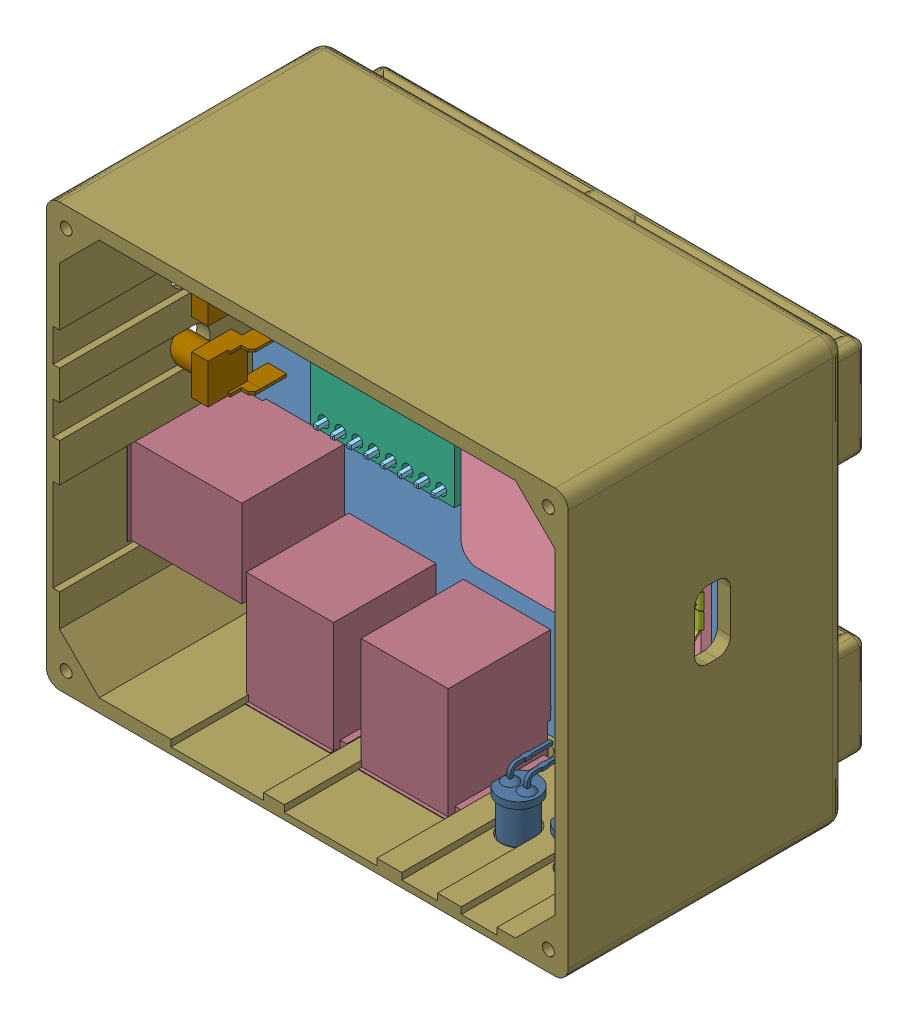
SolidWorks assembly MainDevice, configuration Default. Lengths in mm.
Overall size (81.7 66.7 48).
21 component instances, 16 part files, 51 mates.
Components (placement in the parent):
- main-pcb-1: main-pcb [Default] at (15.5419 -12.6286 71.3403) size (72 56 1.6)
- Pin Header40-1: Pin Header40 [Default] at (39.7853 10.197 72.9403) x (-1 0 0) z (0 0 1) size (51.3 5.33 17.39)
- pinStrip40-1: pinStrip40 [Default] at (-8.2247 9.871 86.5203) x (1 0 0) z (0 0 -1) size (50.8 5.08 11.94)
- Raspberry Pi Zero 2 W-1: Raspberry Pi Zero 2 W [Default] at (15.8053 -2.859 87.0663) x (1 0 0) z (0 -1 0) size (65.8 5.05 30.58) (hidden)
- baterryChargerPCB-1: baterryChargerPCB [Default] at (33.3919 -8.6084 75.4803) x (-1 0 0) z (0 0 1) size (36.3 22.9 1.6)
- 8pins-1: 8pins [Default] at (20.9419 1.6016 78.4803) x (1 0 0) z (0 0 -1) size (20.28 2.5 11.54)
- IMU-PCB-1: IMU-PCB [Default] at (3.3577 -5.3013 75.4803) size (21.8 17.2 1.6)
- 8pins-2: 8pins [Default] at (12.2777 -12.5813 78.4803) x (-1 0 0) z (0 0 -1) size (20.28 2.5 11.54)
- MicroUSB Port, Raspberry Pi Zero 2 W-1: MicroUSB Port, Raspberry Pi Zero 2 W [Default] at (49.3967 -8.6084 77.0803) x (0 1 0) z (1 0 0) size (7.97 2.92 5.43)
- baterryConector-1: baterryConector [Default] at (40.7919 -16.4084 78.6803) x (1 0 0) z (0 -1 0) size (6 7.7 7.3)
- button-1: button [Default] at (-17.2581 3.0321 76.8522) x (0 -1 0) z (-1 0 0) size (6 11.91 9.99)
- button-2: button [Default] at (-17.2581 -7.5747 76.8522) x (0 -1 0) z (-1 0 0) size (6 11.91 9.99)
- led-1: led [Default] at (41.0782 -35.6926 82.166) size (5.41 10.96 9.16)
- led-2: led [Default] at (32.0651 -35.4033 82.177) size (5.41 10.96 9.16)
- battery-1: battery [Default] at (13.9578 -6.0356 69.8403) x (-1 0 0) z (0 0 -1) size (59.2 29.3 9.7)
- encapsuladoMain-1: encapsuladoMain [Default] at (15.0419 -12.6286 58.1403) x (1 0 0) z (0 -1 0) size (79 48 64)
- otg-1: otg [Default] at (-10.4122 -26.7049 90.9313) x (-1 0 0) z (0 0 1) size (36.6 18.2 12.4) (hidden)
- tapa-main-1: tapa-main [Default] at (15.0419 -12.6286 156.1403) x (0 -1 0) z (0 0 -1) size (64 79 6) (hidden)
- rj11jack-1: rj11jack [Default] at (0.7219 -37.0286 72.9403) size (15.2 20.6 20)
- rj11jack-2: rj11jack [Default] at (-16.8581 -24.6336 72.9403) x (0 -1 0) z (0 0 1) size (15.2 20.6 20)
- rj11jack-3: rj11jack [Default] at (18.0719 -37.0286 72.9403) size (15.2 20.6 20)
Mates (geometry in assembly coordinates):
- Coincident5: coincident anti-aligned: plane of main-pcb-1 through (15.5419 -12.6286 72.9403) normal (0 0 1); plane of Pin Header40-1 through (-8.4747 8.927 72.9403) normal (0 0 -1)
- Parallel1: parallel anti-aligned: plane of main-pcb-1 through (47.5419 15.3714 72.9403) normal (0 1 0); plane of Pin Header40-1 through (15.9053 6.141 75.4803) normal (0 -1 0)
- Coincident8: coincident anti-aligned: plane of pinStrip40-1 through (41.0513 11.141 86.2663) normal (0 0 1); plane of Raspberry Pi Zero 2 W-1 through (15.8053 -2.859 86.2663) normal (0 0 -1)
- Parallel2: parallel aligned: plane of pinStrip40-1 through (39.0193 11.141 86.5203) normal (0 1 0); plane of Raspberry Pi Zero 2 W-1 through (-16.6947 12.141 87.8663) normal (0 1 0)
- Distance2: distance = 1 mm aligned: plane of pinStrip40-1 through (39.0193 11.141 86.5203) normal (0 1 0); plane of Raspberry Pi Zero 2 W-1 through (-16.6947 12.141 87.8663) normal (0 1 0)
- Distance3: distance = 7 mm aligned: plane of pinStrip40-1 through (41.3053 8.601 83.9803) normal (1 0 0); plane of Raspberry Pi Zero 2 W-1 through (48.3053 12.141 87.8663) normal (1 0 0)
- Coincident13: coincident anti-aligned: plane of Pin Header40-1 through (15.9053 6.141 83.9803) normal (0 0 1); plane of pinStrip40-1 through (-8.2247 8.601 83.9803) normal (0 0 -1)
- Coincident14: coincident aligned: plane of Pin Header40-1 through (15.9053 11.141 83.9803) normal (0 1 0); plane of pinStrip40-1 through (36.4793 11.141 86.5203) normal (0 1 0)
- Coincident15: coincident aligned: plane of Pin Header40-1 through (41.3053 8.641 75.4803) normal (1 0 0); plane of pinStrip40-1 through (41.3053 8.601 83.9803) normal (1 0 0)
- Coincident16: coincident anti-aligned: plane of baterryChargerPCB-1 through (17.7819 0.3016 75.4803) normal (0 0 -1); plane of 8pins-1 through (20.9419 1.6016 75.4803) normal (0 0 1)
- Parallel4: parallel aligned: plane of baterryChargerPCB-1 through (17.7819 2.8416 77.0803) normal (0 1 0); plane of 8pins-1 through (29.8119 2.8516 75.4803) normal (0 1 0)
- Distance5: distance = 0.01 mm aligned: plane of baterryChargerPCB-1 through (17.7819 2.8416 77.0803) normal (0 1 0); plane of 8pins-1 through (39.9719 2.8516 75.4803) normal (0 1 0)
- Distance6: distance = 11.57 mm aligned: plane of baterryChargerPCB-1 through (51.5419 0.3016 77.0803) normal (1 0 0); plane of 8pins-1 through (39.9719 0.3516 75.4803) normal (1 0 0)
- Coincident21: coincident anti-aligned: plane of main-pcb-1 through (15.5419 -12.6286 72.9403) normal (0 0 1); plane of 8pins-1 through (38.7219 1.6016 72.9403) normal (0 0 -1)
- Coincident22: coincident anti-aligned: plane of IMU-PCB-1 through (3.3577 -5.3013 75.4803) normal (0 0 -1); plane of 8pins-2 through (12.2777 -12.5813 75.4803) normal (0 0 1)
- Parallel5: parallel aligned: plane of IMU-PCB-1 through (14.2577 -13.9013 77.0803) normal (1 0 0); plane of 8pins-2 through (13.5277 -13.8313 75.4803) normal (1 0 0)
- Distance7: distance = 0.07 mm aligned: plane of 8pins-2 through (11.0277 -13.8313 75.4803) normal (0 -1 0); plane of IMU-PCB-1 through (14.2577 -13.9013 77.0803) normal (0 -1 0)
- Distance8: distance = 0.73 mm aligned: plane of 8pins-2 through (13.5277 -13.8313 75.4803) normal (1 0 0); plane of IMU-PCB-1 through (14.2577 -13.9013 77.0803) normal (1 0 0)
- Coincident26: coincident anti-aligned: plane of main-pcb-1 through (15.5419 -12.6286 72.9403) normal (0 0 1); plane of 8pins-2 through (12.2777 -12.5813 72.9403) normal (0 0 -1)
- Coincident27: coincident aligned: plane of main-pcb-1 through (51.5419 -36.6286 72.9403) normal (1 0 0); plane of baterryChargerPCB-1 through (51.5419 0.3016 77.0803) normal (1 0 0)
- Coincident28: coincident anti-aligned: plane of baterryChargerPCB-1 through (17.7819 0.3016 77.0803) normal (0 0 1); plane of MicroUSB Port, Raspberry Pi Zero 2 W-1 through (46.8467 -6.012 77.0803) normal (0 0 -1)
- Parallel6: parallel aligned: plane of baterryChargerPCB-1 through (17.7819 2.8416 77.0803) normal (0 1 0); plane of MicroUSB Port, Raspberry Pi Zero 2 W-1 through (46.8467 -4.8584 78.9803) normal (0 1 0)
- Coincident30: coincident anti-aligned: line of baterryChargerPCB-1 through (51.5419 -17.5184 77.0803) axis (0 1 0); line of MicroUSB Port, Raspberry Pi Zero 2 W-1 through (51.5419 -8.6584 77.0803) axis (0 -1 0)
- Distance9: distance = 7.7 mm aligned: plane of MicroUSB Port, Raspberry Pi Zero 2 W-1 through (46.8467 -4.8584 78.9803) normal (0 1 0); plane of baterryChargerPCB-1 through (17.7819 2.8416 77.0803) normal (0 1 0)
- Coincident34: coincident anti-aligned: plane of baterryChargerPCB-1 through (17.7819 0.3016 77.0803) normal (0 0 1); plane of baterryConector-1 through (42.4169 -20.0584 77.0803) normal (0 0 -1)
- Coincident35: coincident aligned: plane of baterryChargerPCB-1 through (17.7819 -20.0584 77.0803) normal (0 -1 0); plane of baterryConector-1 through (40.7919 -20.0584 78.6803) normal (0 -1 0)
- Distance10: distance = 9.5 mm aligned: plane of baterryConector-1 through (42.0419 -16.4084 78.6803) normal (1 0 0); plane of baterryChargerPCB-1 through (51.5419 0.3016 77.0803) normal (1 0 0)
- Coincident37: coincident anti-aligned: plane of main-pcb-1 through (15.5419 -12.6286 72.9403) normal (0 0 1); plane of button-1 through (-16.3699 3.0321 72.9403) normal (0 0 -1)
- Coincident38: coincident anti-aligned: plane of main-pcb-1 through (15.5419 -12.6286 72.9403) normal (0 0 1); plane of button-2 through (-16.3699 -7.5747 72.9403) normal (0 0 -1)
- Parallel7: parallel aligned: plane of main-pcb-1 through (-20.4581 -36.6286 72.9403) normal (-1 0 0); plane of button-2 through (-19.7581 -7.5747 76.8522) normal (-1 0 0)
- Parallel8: parallel aligned: plane of main-pcb-1 through (-20.4581 -36.6286 72.9403) normal (-1 0 0); plane of button-1 through (-19.7581 3.0321 76.8522) normal (-1 0 0)
- Distance14: distance = 1.5 mm anti-aligned: plane of battery-1 through (13.9578 -6.0356 69.8403) normal (0 0 1); plane of main-pcb-1 through (15.5419 -12.6286 71.3403) normal (0 0 -1)
- Parallel9: parallel aligned: plane of main-pcb-1 through (-20.4581 -36.6286 72.9403) normal (-1 0 0); plane of battery-1 through (-12.1422 -20.6856 60.1403) normal (-1 0 0)
- Coincident41: coincident anti-aligned: plane of battery-1 through (13.9578 -6.0356 60.1403) normal (0 0 -1); plane of encapsuladoMain-1 through (15.0419 -12.6286 60.1403) normal (0 0 1)
- Distance17: distance = 2 mm anti-aligned: plane of encapsuladoMain-1 through (52.5419 -42.6286 100.1403) normal (0 1 0); plane of main-pcb-1 through (47.5419 -40.6286 72.9403) normal (0 -1 0)
- Distance18: distance = 2 mm: plane of encapsuladoMain-1 through (-22.4581 -42.6286 100.1403) normal (1 0 0); line of main-pcb-1 through (-20.4581 11.3714 72.9403) axis (0 -1 0)
- Distance22: distance = 0.8 mm aligned: plane of button-1 through (-25.2581 0.0321 79.8522) normal (-1 0 0); plane of encapsuladoMain-1 through (-24.4581 -44.6286 60.1403) normal (-1 0 0)
- Distance23: distance = 0.8 mm aligned: plane of button-2 through (-25.2581 -10.5747 79.8522) normal (-1 0 0); plane of encapsuladoMain-1 through (-24.4581 -44.6286 60.1403) normal (-1 0 0)
- Parallel10: parallel anti-aligned: plane of encapsuladoMain-1 through (15.0419 -12.6286 100.1403) normal (0 0 1); plane of tapa-main-1 through (15.0419 -12.6286 150.1403) normal (0 0 -1)
- Coincident43: coincident aligned: plane of encapsuladoMain-1 through (54.5419 -44.6286 60.1403) normal (0 -1 0); plane of tapa-main-1 through (54.5419 -44.6286 154.1403) normal (0 -1 0)
- Coincident44: coincident aligned: plane of encapsuladoMain-1 through (-24.4581 -44.6286 60.1403) normal (-1 0 0); plane of tapa-main-1 through (-24.4581 -44.6286 154.1403) normal (-1 0 0)
- LimitDistance1: limit distance = 50 mm anti-aligned: plane of tapa-main-1 through (15.0419 -12.6286 150.1403) normal (0 0 -1); plane of encapsuladoMain-1 through (15.0419 -12.6286 100.1403) normal (0 0 1)
- Coincident45: coincident anti-aligned: plane of main-pcb-1 through (15.5419 -12.6286 72.9403) normal (0 0 1); plane of rj11jack-1 through (0.7219 -37.0286 72.9403) normal (0 0 -1)
- Concentric1: concentric aligned: circle of main-pcb-1; circle of rj11jack-1
- Parallel11: parallel aligned: plane of main-pcb-1 through (47.5419 -40.6286 72.9403) normal (0 -1 0); plane of rj11jack-1 through (7.3219 -47.3286 88.4403) normal (0 -1 0)
- Coincident47: coincident anti-aligned: plane of main-pcb-1 through (15.5419 -12.6286 72.9403) normal (0 0 1); plane of rj11jack-2 through (-16.8581 -24.6336 72.9403) normal (0 0 -1)
- Concentric2: concentric aligned: circle of main-pcb-1; circle of rj11jack-2
- Parallel12: parallel aligned: plane of main-pcb-1 through (-20.4581 -36.6286 72.9403) normal (-1 0 0); plane of rj11jack-2 through (-27.1581 -31.2336 88.4403) normal (-1 0 0)
- Concentric3: concentric aligned: circle of main-pcb-1; circle of rj11jack-3
- Coincident49: coincident anti-aligned: plane of main-pcb-1 through (15.5419 -12.6286 72.9403) normal (0 0 1); plane of rj11jack-3 through (18.0719 -37.0286 72.9403) normal (0 0 -1)
- Parallel13: parallel aligned: plane of rj11jack-3 through (24.6719 -47.3286 88.4403) normal (0 -1 0); plane of main-pcb-1 through (47.5419 -40.6286 72.9403) normal (0 -1 0)
